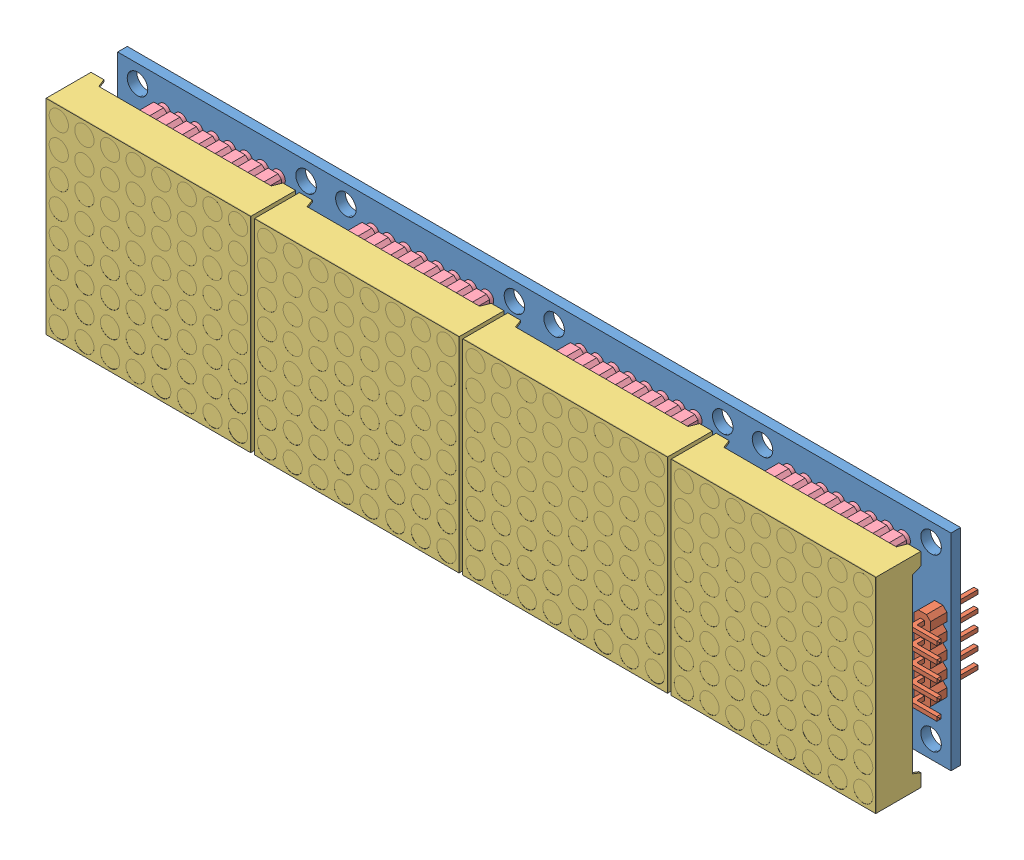
SolidWorks assembly LED Matrix 32x8 - 4 Modules 8x8 with MAX7219 , configuration Default. Lengths in mm.
Overall size (132.87 34 17.7).
18 component instances, 5 part files, 16 mates.
Components (placement in the parent):
- PCB-1: PCB [Default] at (20.1471 25.9698 38.68) x (-1 0 0) z (0 0 -1) size (131.5 34 2.5)
- 90 5xHeader Pins-2: 90 5xHeader Pins [Default] at (35.7346 25.2698 38.88) x (0 1 0) z (-1 0 0) size (12.7 10.36 5.54)
- 1088AS-1: 1088AS [Default] at (4.5446 41.8698 50.38) x (0 -1 0) z (-1 0 0) size (31.81 10.5 31.8)
- 8x female rounded header-1: 8x female rounded header [Default] at (21.7146 13.9698 42.88) size (20.32 2.54 7.43)
- 8x female rounded header-2: 8x female rounded header [Default] at (21.7146 37.9698 42.88) size (20.32 2.54 7.43)
- MAX7219--3DModel-STEP-56544-1: MAX7219--3DModel-STEP-56544 [Défaut] at (28.1268 25.9698 37) x (1 0 0) z (0 -1 0) size (15.4 1.59 10.98)
- MAX7219--3DModel-STEP-56544-2: MAX7219--3DModel-STEP-56544 [Défaut] at (-4.2532 25.9698 37) x (1 0 0) z (0 -1 0) size (15.4 1.59 10.98)
- MAX7219--3DModel-STEP-56544-3: MAX7219--3DModel-STEP-56544 [Défaut] at (-36.6332 25.9698 37) x (1 0 0) z (0 -1 0) size (15.4 1.59 10.98)
- MAX7219--3DModel-STEP-56544-4: MAX7219--3DModel-STEP-56544 [Défaut] at (-69.0132 25.9698 37) x (1 0 0) z (0 -1 0) size (15.4 1.59 10.98)
- 8x female rounded header-3: 8x female rounded header [Default] at (-10.6654 37.9698 42.88) size (20.32 2.54 7.43)
- 8x female rounded header-4: 8x female rounded header [Default] at (-43.0454 37.9698 42.88) size (20.32 2.54 7.43)
- 8x female rounded header-5: 8x female rounded header [Default] at (-75.4254 37.9698 42.88) size (20.32 2.54 7.43)
- 8x female rounded header-6: 8x female rounded header [Default] at (-10.6654 13.9698 42.88) size (20.32 2.54 7.43)
- 8x female rounded header-7: 8x female rounded header [Default] at (-43.0454 13.9698 42.88) size (20.32 2.54 7.43)
- 8x female rounded header-8: 8x female rounded header [Default] at (-75.4254 13.9698 42.88) size (20.32 2.54 7.43)
- 1088AS-2: 1088AS [Default] at (-27.8354 41.8698 50.38) x (0 -1 0) z (-1 0 0) size (31.81 10.5 31.8)
- 1088AS-3: 1088AS [Default] at (-60.2154 41.8698 50.38) x (0 -1 0) z (-1 0 0) size (31.81 10.5 31.8)
- 1088AS-4: 1088AS [Default] at (-92.5954 41.8698 50.38) x (0 -1 0) z (-1 0 0) size (31.81 10.5 31.8)
Mates (geometry in assembly coordinates):
- Coincident2: coincident anti-aligned: plane of PCB - Copie-1 through (20.1471 25.9698 38.68) normal (0 0 1); plane of 90 5xHeader Pins-2 through (34.4346 30.3698 38.68) normal (0 0 -1)
- Width6: width: plane of 90 5xHeader Pins-2 through (34.7546 30.0498 38.68) normal (0 -1 0); plane of 90 5xHeader Pins-2 through (34.1146 30.6898 38.68) normal (0 1 0); cylinder of PCB-1 through (34.4346 30.3698 35.7658) axis (0 0 1) radius 0.5
- Width7: width: plane of 90 5xHeader Pins-2 through (34.7546 20.5298 38.68) normal (1 0 0); plane of 90 5xHeader Pins-2 through (34.1146 19.8898 38.68) normal (-1 0 0); cylinder of PCB-1 through (34.4346 20.2098 35.7658) axis (0 0 1) radius 0.5
- Width8: width: plane of 90 5xHeader Pins-2 through (34.7546 30.6898 38.68) normal (1 0 0); plane of 90 5xHeader Pins-2 through (34.1146 30.0498 38.68) normal (-1 0 0); cylinder of PCB-1 through (34.4346 30.3698 35.7658) axis (0 0 1) radius 0.5
- Concentric3: concentric aligned: cylinder of PCB - Copie-1 through (11.5546 13.9698 35.7658) axis (0 0 1) radius 0.5; cylinder of 1088AS-1 through (11.5546 13.9698 39.88) axis (0 0 1) radius 0.25
- Concentric4: concentric aligned: cylinder of PCB - Copie-1 through (29.3346 13.9698 35.7658) axis (0 0 1) radius 0.5; cylinder of 1088AS-1 through (29.3346 13.9698 39.88) axis (0 0 1) radius 0.25
- Distance1: distance = 13.2 mm anti-aligned: plane of 1088AS-1 through (4.5446 41.8698 50.38) normal (0 0 1); plane of PCB - Copie-1 through (20.1471 25.9698 37.18) normal (0 0 -1)
- Coincident5: coincident anti-aligned: plane of PCB - Copie-1 through (20.1471 25.9698 38.68) normal (0 0 1); plane of 8x female rounded header-1 through (11.5546 13.9698 38.68) normal (0 0 -1)
- Concentric5: concentric aligned: cylinder of PCB - Copie-1 through (11.5546 13.9698 35.7658) axis (0 0 1) radius 0.5; cylinder of 8x female rounded header-1 through (11.5546 13.9698 35.45) axis (0 0 1) radius 0.255
- Concentric6: concentric aligned: cylinder of PCB - Copie-1 through (29.3346 13.9698 35.7658) axis (0 0 1) radius 0.5; cylinder of 8x female rounded header-1 through (29.3346 13.9698 35.45) axis (0 0 1) radius 0.255
- Concentric7: concentric aligned: cylinder of PCB - Copie-1 through (29.3346 37.9698 35.7658) axis (0 0 1) radius 0.5; cylinder of 8x female rounded header-2 through (29.3346 37.9698 35.45) axis (0 0 1) radius 0.255
- Concentric8: concentric aligned: cylinder of PCB - Copie-1 through (11.5546 37.9698 35.7658) axis (0 0 1) radius 0.5; cylinder of 8x female rounded header-2 through (11.5546 37.9698 35.45) axis (0 0 1) radius 0.255
- Coincident6: coincident anti-aligned: plane of PCB - Copie-1 through (20.1471 25.9698 38.68) normal (0 0 1); plane of 8x female rounded header-2 through (24.2546 37.9698 38.68) normal (0 0 -1)
- Coïncidente1: coincident anti-aligned: plane of PCB - Copie-1 through (20.1471 25.9698 38.68) normal (0 0 1); plane of MAX7219--3DModel-STEP-56544-1 through (28.1268 25.9698 38.68) normal (0 0 -1)
- Symétrique1: symmetric aligned: plane of PCB - Copie-1 through (3.9596 9.9698 37.18) normal (0 -1 0); plane of PCB - Copie-1 through (3.9596 41.9698 37.18) normal (0 1 0); plane of MAX7219--3DModel-STEP-56544-1 through (28.1268 25.9698 37) normal (0 -1 0)
- Distance2: distance = 8.0757 mm aligned: plane of MAX7219--3DModel-STEP-56544-1 through (28.2589 29.4623 39.6147) normal (1 0 0); plane of PCB - Copie-1 through (36.3346 9.9698 37.18) normal (1 0 0)
